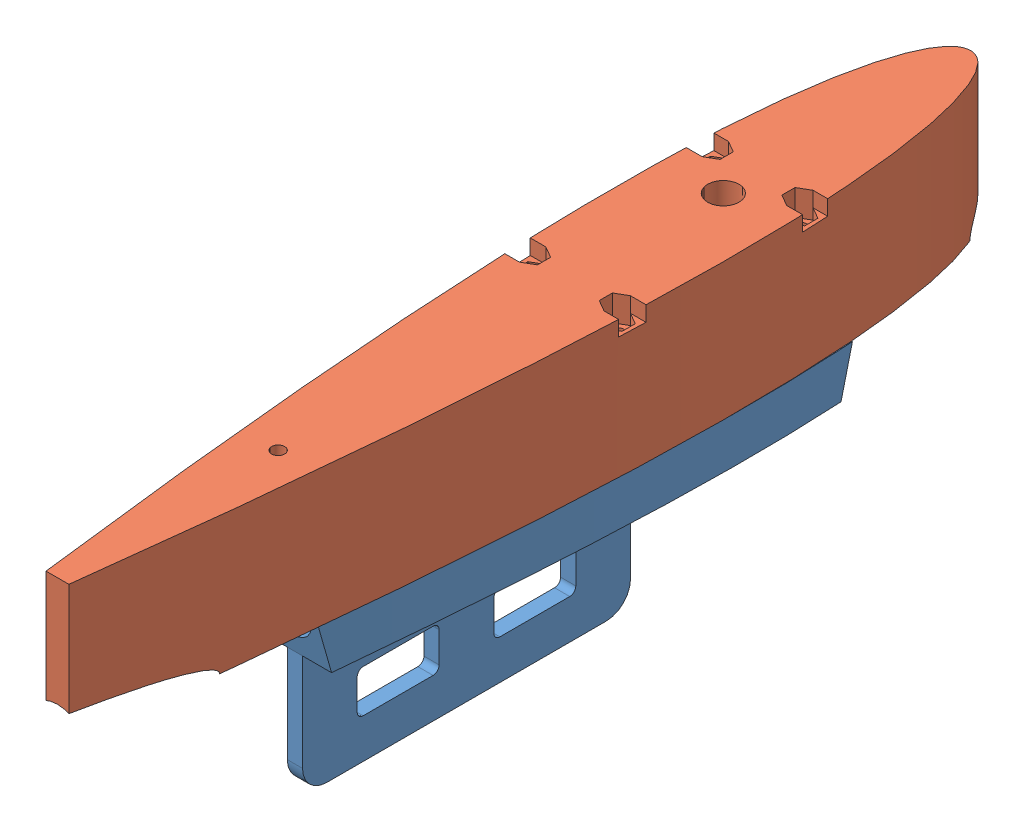
SolidWorks assembly tail_skidAssem_v1b, configuration Default. Lengths in mm.
Overall size (39.02 100 303.25).
2 component instances, 2 part files, 15 mates.
Components (placement in the parent):
- tail_skidSkid_v1.3-1: tail_skidSkid_v1.3 [Default] at (0 -61.5 -4) x (0 0 1) z (0 1 0) size (168.75 39.02 55)
- tail_skidSkidUpper_v1.3-1: tail_skidSkidUpper_v1.3 [Default] at (0 -61.5 0) x (0 0 1) z (0 1 0) size (303.25 39.02 57)
Mates (geometry in assembly coordinates):
- Coincident1: coincident anti-aligned: plane of ? through (0 0 0) normal (0 -1 0); plane of assembly through (0 0 0) normal (0 1 0)
- Coincident2: coincident anti-aligned: plane of ? through (0 0 0) normal (0 0 -1); plane of assembly through (0 0 0) normal (0 0 1)
- Coincident3: coincident aligned: plane of ? through (0 0 0) normal (1 0 0); plane of assembly through (0 0 0) normal (1 0 0)
- Coincident4: coincident anti-aligned: plane of ? through (0 -1.5 0) normal (0 -1 0); plane of tail_skidSkidUpper_v1.3-1 through (79.6856 -1.5 -32.8829) normal (0 1 0)
- Concentric1: concentric anti-aligned: cylinder of ? through (0 0 -48.75) axis (0 -1 0) radius 5.5; cylinder of tail_skidSkidUpper_v1.3-1 through (0 -31.5 -48.75) axis (0 1 0) radius 5.15
- Parallel1: parallel anti-aligned: cylinder of ? through (0 0 -146.25) axis (0 -1 0) radius 2.5; cylinder of tail_skidSkidUpper_v1.3-1 through (-143.4341 -31.5 -77.3108) axis (0 1 0) radius 2.15
- Coincident6: coincident anti-aligned: plane of tail_skidSkid_v1.3-1 through (0 -46.5 -4) normal (0 1 0); plane of tail_skidSkidUpper_v1.3-1 through (0 -46.5 0) normal (0 -1 0)
- Concentric3: concentric anti-aligned: cylinder of tail_skidSkid_v1.3-1 through (13.9 -46.5 70) axis (0 -1 0) radius 2.25; cylinder of tail_skidSkidUpper_v1.3-1 through (13.9 -48.784 70) axis (0 1 0) radius 2.25
- Concentric4: concentric anti-aligned: cylinder of tail_skidSkid_v1.3-1 through (-13.9 -46.5 70) axis (0 -1 0) radius 2.25; cylinder of tail_skidSkidUpper_v1.3-1 through (-13.9 -48.784 70) axis (0 1 0) radius 2.25
- Coincident8: coincident anti-aligned: plane of tail_skidSkidUpper_v1.3-1 through (12.2651 -1.5 0.9311) normal (0 1 0); plane of ? through (0 -1.5 0) normal (0 -1 0)
- Concentric6: concentric anti-aligned: cylinder of tail_skidSkidUpper_v1.3-1 through (0 -31.5 81.25) axis (0 1 0) radius 5.15; cylinder of ? through (0 0 81.25) axis (0 -1 0) radius 5.5
- Coincident9: coincident anti-aligned: plane of ? through (0 0 0) normal (0 -1 0); plane of assembly through (0 0 0) normal (0 1 0)
- Coincident10: coincident anti-aligned: plane of ? through (0 0 0) normal (-1 0 0); plane of assembly through (0 0 0) normal (1 0 0)
- Coincident11: coincident aligned: plane of ? through (0 0 0) normal (0 0 1); plane of assembly through (0 0 0) normal (0 0 1)
- Concentric7: concentric anti-aligned: cylinder of tail_skidSkidUpper_v1.3-1 through (0 -31.5 227.5) axis (0 1 0) radius 2.15; cylinder of ? through (0 0 227.5) axis (0 -1 0) radius 2.5
